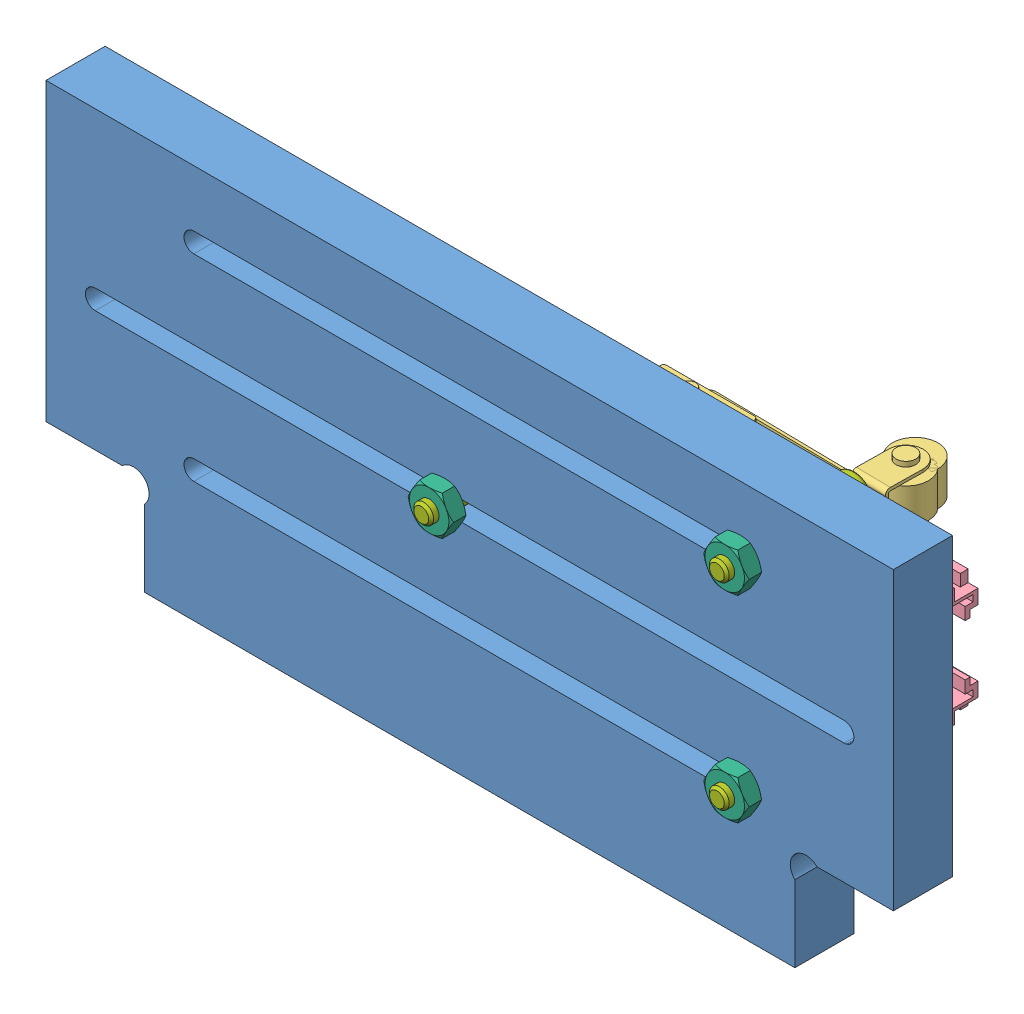
SolidWorks assembly fdc_ouvert, configuration Défaut. Lengths in mm.
Overall size (86 40 30.8).
14 component instances, 7 part files, 25 mates.
Components (placement in the parent):
- fdc-platine-1: fdc-platine [Défaut] at (140.8628 -70 0) x (0 0 1) z (0 -1 0) size (6 86 40)
- Grove microswitch v1.0-1: Grove microswitch v1.0 [Défaut] at (-27.4996 23.25 -3.344) x (-1 0 0) z (0 -1 0) size (41.8 22.4 23.6)
  - PCB grove 20x40-1: PCB grove 20x40 [Défaut] at (-1.988 -1.344 0) size (41.8 1.6 23.6)
  - microswitch 10T85-1: microswitch 10T85 [Défaut] at (9.562 0.256 0) size (22.48 22.4 6.4)
  - Connecteur Grove (coudé CMS)-1: Connecteur Grove (coudé CMS) [Défaut] at (-21.488 0.256 0) x (0 0 -1) z (0 1 0) size (12 10 5)
- entretoise-grove-1: entretoise-grove [Défaut] at (-45.5117 23.25 -2) x (1 0.000242 0) z (0 0 1) size (4 4 2)
- entretoise-grove-2: entretoise-grove [Défaut] at (-15.5117 33.25 -2) size (4 4 2)
- entretoise-grove-3: entretoise-grove [Défaut] at (-15.5117 13.25 -2) size (4 4 2)
- ecrou-h-1: ecrou-h [6007 HU M2] at (-45.5117 23.25 7.6) x (0.866025 -0.5 0) z (-0.5 -0.866025 0) size (4 1.6 4.62)
- ecrou-h-2: ecrou-h [6007 HU M2] at (-15.5117 33.25 7.6) x (0.866025 0.5 0) z (0.5 -0.866025 0) size (4 1.6 4.62)
- ecrou-h-3: ecrou-h [6007 HU M2] at (-15.5117 13.25 7.6) x (-0.866025 0.5 0) z (0.5 0.866025 0) size (4 1.6 4.62)
- vis-chc-1: vis-chc [Vis CHC M2x12] at (-15.5117 33.25 -3.6) x (1 0 0) z (0 1 0) size (3.8 14 3.8)
- vis-chc-2: vis-chc [Vis CHC M2x12] at (-15.5117 13.25 -3.6) x (1 0 0) z (0 1 0) size (3.8 14 3.8)
- vis-chc-3: vis-chc [Vis CHC M2x12] at (-45.5117 23.25 -3.6) x (0.999585 0.028802 0) z (-0.028802 0.999585 0) size (3.8 14 3.8)
Mates (geometry in assembly coordinates):
- Coaxiale1: concentric anti-aligned: cylinder of Grove microswitch v1.0-1/PCB grove 20x40-1 through (-15.5117 13.25 -3.6) axis (0 0 1) radius 1.1; cylinder of entretoise-grove-3 through (-15.5117 13.25 0) axis (0 0 -1) radius 1.2
- Coïncidente4: coincident anti-aligned: plane of Grove microswitch v1.0-1/PCB grove 20x40-1 through (-25.5117 23.25 -2) normal (0 0 1); plane of entretoise-grove-3 through (-15.5117 13.25 -2) normal (0 0 -1)
- Coaxiale2: concentric anti-aligned: cylinder of Grove microswitch v1.0-1/PCB grove 20x40-1 through (-45.5117 23.25 -3.6) axis (0 0 1) radius 1.1; cylinder of entretoise-grove-1 through (-45.5117 23.25 0) axis (0 0 -1) radius 1.2
- Coïncidente5: coincident anti-aligned: plane of Grove microswitch v1.0-1/PCB grove 20x40-1 through (-25.5117 23.25 -2) normal (0 0 1); plane of entretoise-grove-1 through (-45.5117 23.25 -2) normal (0 0 -1)
- Coaxiale3: concentric anti-aligned: cylinder of Grove microswitch v1.0-1/PCB grove 20x40-1 through (-15.5117 33.25 -3.6) axis (0 0 1) radius 1.1; cylinder of entretoise-grove-2 through (-15.5117 33.25 0) axis (0 0 -1) radius 1.2
- Coïncidente6: coincident anti-aligned: plane of Grove microswitch v1.0-1/PCB grove 20x40-1 through (-25.5117 23.25 -2) normal (0 0 1); plane of entretoise-grove-2 through (-15.5117 33.25 -2) normal (0 0 -1)
- Coïncidente7: coincident anti-aligned: plane of cfc-platine-1 through (-8.8686 8.8686 0) normal (0 0 -1); plane of entretoise-grove-1 through (-45.5117 23.25 0) normal (0 0 1)
- Parallèle4: parallel aligned: plane of cfc-platine-1 through (-86 40 6) normal (-1 0 0); plane of Grove microswitch v1.0-1/PCB grove 20x40-1 through (-45.5117 23.25 -3.6) normal (-1 0 0)
- Parallèle3: parallel aligned: plane of cfc-platine-1 through (-10 0 6) normal (0 -1 0); plane of Grove microswitch v1.0-1/PCB grove 20x40-1 through (-25.5117 13.25 -3.6) normal (0 -1 0)
- Coaxiale4: concentric anti-aligned: cylinder of Grove microswitch v1.0-1/PCB grove 20x40-1 through (-15.5117 33.25 -3.6) axis (0 0 1) radius 1.1; cylinder of vis-chc-1 through (-15.5117 33.25 8.4) axis (0 0 -1) radius 1
- Coaxiale5: concentric anti-aligned: cylinder of Grove microswitch v1.0-1/PCB grove 20x40-1 through (-45.5117 23.25 -3.6) axis (0 0 1) radius 1.1; cylinder of vis-chc-3 through (-45.5117 23.25 8.4) axis (0 0 -1) radius 1
- Coaxiale6: concentric anti-aligned: cylinder of Grove microswitch v1.0-1/PCB grove 20x40-1 through (-15.5117 13.25 -3.6) axis (0 0 1) radius 1.1; cylinder of vis-chc-2 through (-15.5117 13.25 8.4) axis (0 0 -1) radius 1
- Coïncidente11: coincident anti-aligned: plane of Grove microswitch v1.0-1/PCB grove 20x40-1 through (-25.5117 23.25 -3.6) normal (0 0 -1); plane of vis-chc-3 through (-45.5117 23.25 -3.6) normal (0 0 1)
- Coïncidente12: coincident anti-aligned: plane of Grove microswitch v1.0-1/PCB grove 20x40-1 through (-25.5117 23.25 -3.6) normal (0 0 -1); plane of vis-chc-2 through (-15.5117 13.25 -3.6) normal (0 0 1)
- Coïncidente13: coincident anti-aligned: plane of Grove microswitch v1.0-1/PCB grove 20x40-1 through (-25.5117 23.25 -3.6) normal (0 0 -1); plane of vis-chc-1 through (-15.5117 33.25 -3.6) normal (0 0 1)
- Coaxiale7: concentric anti-aligned: cylinder of ecrou-h-2 through (-15.5117 33.25 6) axis (0 0 1) radius 0.7835; cylinder of vis-chc-1 through (-15.5117 33.25 8.4) axis (0 0 -1) radius 1
- Coaxiale8: concentric anti-aligned: cylinder of ecrou-h-3 through (-15.5117 13.25 6) axis (0 0 1) radius 0.7835; cylinder of vis-chc-2 through (-15.5117 13.25 8.4) axis (0 0 -1) radius 1
- Coaxiale9: concentric anti-aligned: cylinder of ecrou-h-1 through (-45.5117 23.25 6) axis (0 0 1) radius 0.7835; cylinder of vis-chc-3 through (-45.5117 23.25 8.4) axis (0 0 -1) radius 1
- Coïncidente14: coincident anti-aligned: plane of cfc-platine-1 through (-8.8686 8.8686 6) normal (0 0 1); plane of ecrou-h-2 through (-14.357 35.25 6) normal (0 0 -1)
- Coïncidente15: coincident anti-aligned: plane of cfc-platine-1 through (-8.8686 8.8686 6) normal (0 0 1); plane of ecrou-h-1 through (-43.2023 23.25 6) normal (0 0 -1)
- Coïncidente16: coincident anti-aligned: plane of cfc-platine-1 through (-8.8686 8.8686 6) normal (0 0 1); plane of ecrou-h-3 through (-17.8211 13.25 6) normal (0 0 -1)
- Parallèle5: parallel aligned: plane of cfc-platine-1 through (0 40 6) normal (0 1 0); plane of ecrou-h-2 through (-14.357 35.25 6) normal (0 1 0)
- Parallèle6: parallel aligned: plane of ecrou-h-1 through (-44.357 25.25 6) normal (0 1 0); plane of ecrou-h-2 through (-14.357 35.25 6) normal (0 1 0)
- Parallèle7: parallel aligned: plane of ecrou-h-2 through (-14.357 35.25 6) normal (0 1 0); plane of ecrou-h-3 through (-14.357 15.25 6) normal (0 1 0)
- Tangent1: tangent anti-aligned: plane of cfc-platine-1 through (-15 32.25 6) normal (0 1 0); cylinder of vis-chc-1 through (-15.5117 33.25 8.4) axis (0 0 -1) radius 1
